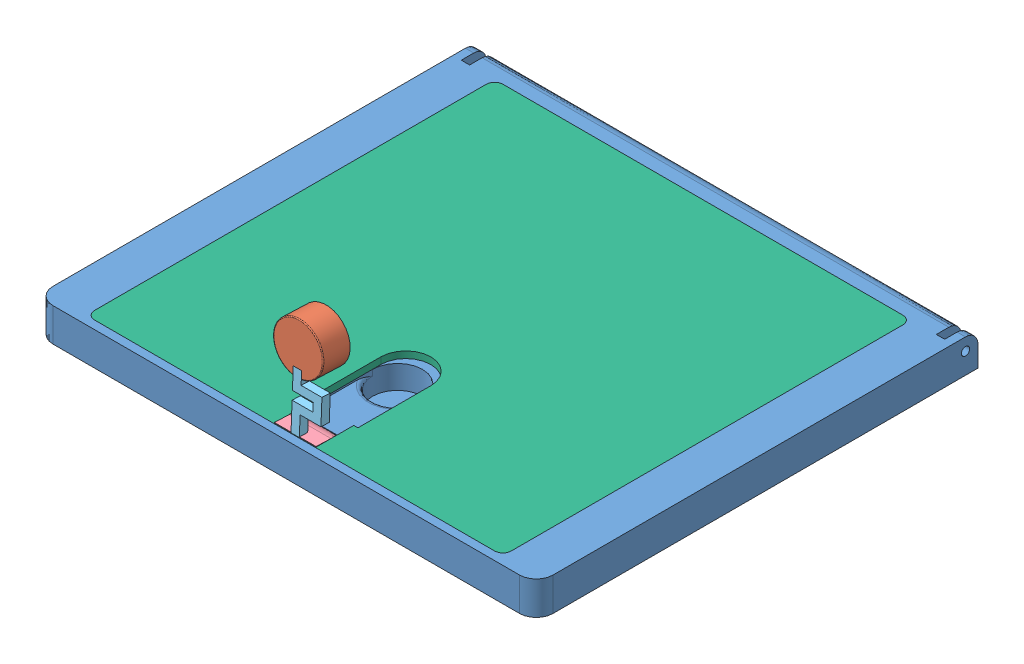
SolidWorks assembly 装配体1, configuration Default. Lengths in mm.
Overall size (120 31.62 106).
6 component instances, 6 part files, 10 mates.
Components (placement in the parent):
- 充电座(连杆)-右-1: 充电座(连杆)-右 [Default] x (0 0 1) z (-1 0 0) size (106 8 120)
- 充电座1-磁吸头套-1: 充电座1-磁吸头套 [Default] at (0 17.6295 -2.8369) x (1 0 0) z (0 0.039521 0.999219) size (12 12 6.5)
- 充电座-磁吸头-1: 充电座-磁吸头 [Default] at (0 17.3727 -9.3318) x (0.998487 0.054953 -0.002173) z (0 -0.039521 -0.999219) size (9.8 9.8 5.2)
- 充电座-磁吸头-转轴-1: 充电座-磁吸头-转轴 [Default] at (-5 -3.6 -5.6) x (0 -0.039521 -0.999219) z (1 0 0) size (7.2 7.2 14)
- 充电座-磁吸线-1: 充电座-磁吸线 [Default] at (-1 13.5536 -4.6772) x (1 0 0) z (0 0.039521 0.999219) size (7 17.18 3.73)
- 充电座(连杆)-盖-1: 充电座(连杆)-盖 [Default] at (-50 -1.6 -100) x (0 0 1) z (0 1 0) size (98 100 1.6)
Mates (geometry in assembly coordinates):
- 重合14: coincident anti-aligned: circle of 充电座1-磁吸头套-1; circle of 充电座-磁吸头-1
- 同心5: concentric anti-aligned: cylinder of 充电座(连杆)-右-1 through (-7 -3.6 -5.6) axis (1 0 0) radius 2; cylinder of 充电座-磁吸头-转轴-1 through (7 -3.6 -5.6) axis (-1 0 0) radius 2
- 重合15: coincident aligned: circle of 充电座(连杆)-右-1; circle of 充电座-磁吸头-转轴-1
- 重合18: coincident aligned: line of 充电座1-磁吸头套-1 through (-1 13.6327 -2.6788) axis (1 0 0); line of 充电座-磁吸线-1 through (-1 13.6327 -2.6788) axis (1 0 0)
- 重合21: coincident aligned: line of 充电座1-磁吸头套-1 through (1 13.6327 -2.6788) axis (0 -0.039521 -0.999219); line of 充电座-磁吸线-1 through (1 13.6327 -2.6788) axis (0 -0.039521 -0.999219)
- 重合22: coincident anti-aligned: line of 充电座-磁吸头-转轴-1 through (1 -2.5347 -2.0393) axis (-1 0 0); line of 充电座-磁吸线-1 through (-1 -2.5347 -2.0393) axis (1 0 0)
- 重合23: coincident aligned: line of 充电座-磁吸头-转轴-1 through (-1 0.1395 -2.1451) axis (0 -0.999219 0.039521); line of 充电座-磁吸线-1 through (-1 6.6381 -2.4021) axis (0 -0.999219 0.039521)
- 重合24: coincident anti-aligned: plane of 充电座(连杆)-右-1 through (0 -1.6 0) normal (0 1 0); plane of 充电座(连杆)-盖-1 through (-50 -1.6 -100) normal (0 -1 0)
- 重合26: coincident anti-aligned: circle of 充电座(连杆)-右-1; circle of 充电座(连杆)-盖-1
- 重合27: coincident anti-aligned: circle of 充电座(连杆)-右-1; circle of 充电座(连杆)-盖-1
